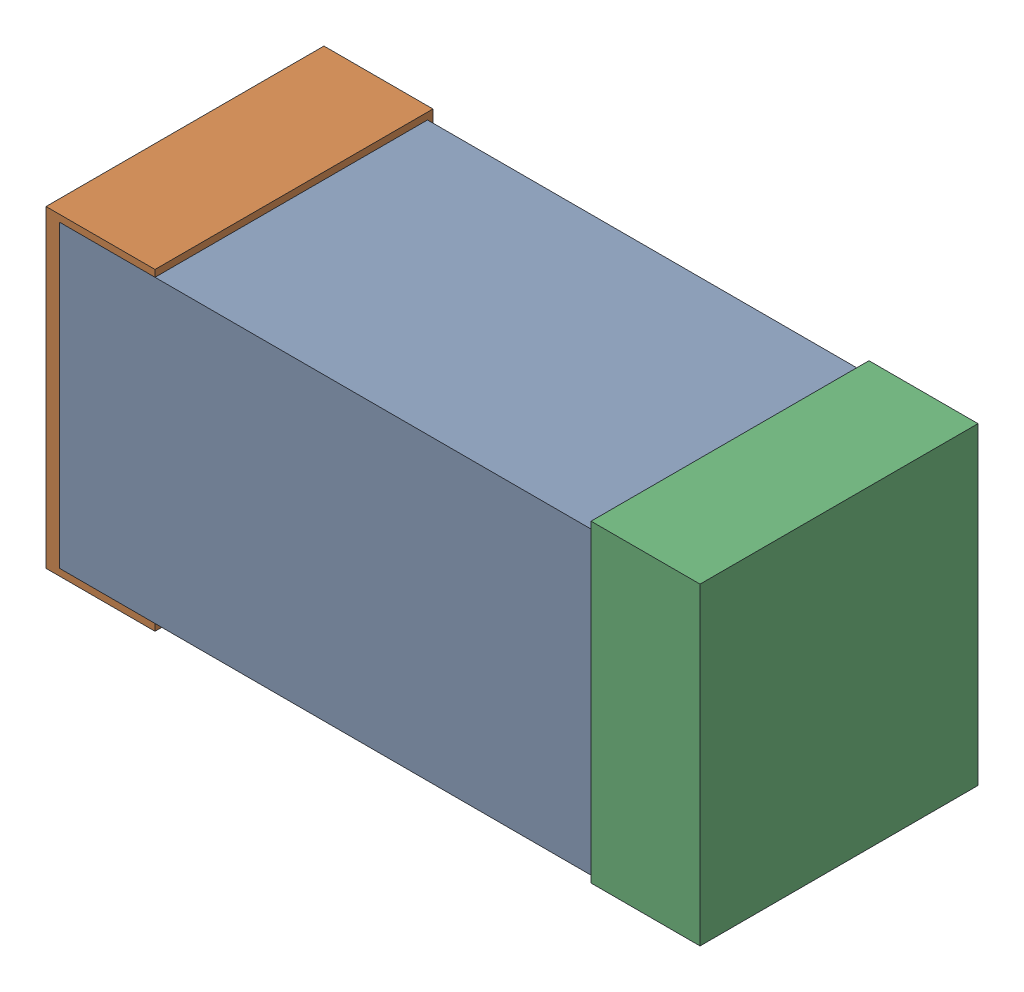
SolidWorks assembly R10, configuration Default. Lengths in mm.
Overall size (1.2 0.58 0.51).
6 component instances, 2 part files, 0 mates.
Components (placement in the parent):
- 384312640-1: 384312640 [Default] at (21.336 40.386 -1.6024) size (1.15 0.55 0.5)
  - Extruded_18-1: Extruded_18 [Default] at origin size (1.15 0.55 0.5)
- 384310976-1: 384310976 [Default] at (20.836 40.386 -1.6124) size (0.2 0.58 0.51)
  - Extruded_19-1: Extruded_19 [Default] at origin size (0.2 0.58 0.51)
- 384310976-2: 384310976 [Default] at (21.836 40.386 -1.6124) size (0.2 0.58 0.51)
  - Extruded_19-1: Extruded_19 [Default] at origin size (0.2 0.58 0.51)
